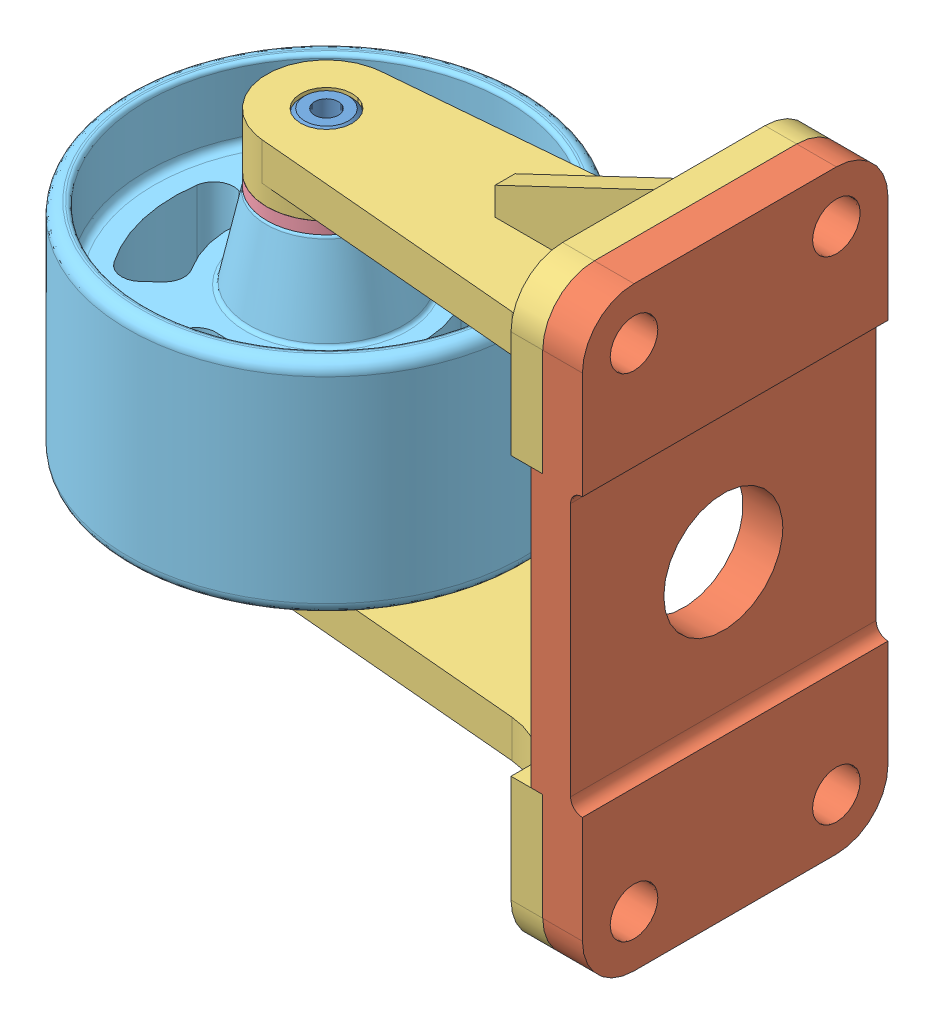
SolidWorks assembly 어셈블리1, configuration 기본. Lengths in mm.
Overall size (163.12 150 120.24).
7 component instances, 5 part files, 15 mates.
Components (placement in the parent):
- 250908_caster_axis-1: 250908_caster_axis [기본] at (-71.4492 13.4699 98) size (20 98 20)
- 250908_caster_base-1: 250908_caster_base [기본] at (31.5508 13.4699 98) x (0 1 0) z (0 0 1) size (150 13 77)
- 250908_caster_bracket-1: 250908_caster_bracket [기본] at (21.5508 -61.5301 98) x (0 0 1) z (0 -1 0) size (77 108 40)
- 250908_caster_bush-1: 250908_caster_bush [기본] at (-71.4492 -21.5301 98) x (0.41057 0 -0.911829) z (0.911829 0 0.41057) size (30 25 30)
- 250908_caster_wheel-1: 250908_caster_wheel [기본] at (-71.4492 14.4699 98) x (-0.228988 0 -0.973429) z (0.973429 0 -0.228988) size (100 62 100)
- 250908_caster_bracket-2: 250908_caster_bracket [기본] at (21.5508 88.4699 98) x (0 0 -1) z (0 1 0) size (77 108 40)
- 250908_caster_bush-3: 250908_caster_bush [기본] at (-71.4492 48.4699 98) x (-0.999987 0 0.00502) z (0.00502 0 0.999987) size (30 25 30)
Mates (geometry in assembly coordinates):
- 동심10: concentric: circle of 250908_caster_base-1; circle of 250908_caster_bracket-2
- 동심16: concentric: circle of 250908_caster_base-1; circle of 250908_caster_bracket-2
- 일치9: coincident: plane of 250908_caster_base-1 through (21.5508 13.4699 98) normal (-1 0 0); plane of 250908_caster_bracket-2 through (21.5508 75.4699 123.5) normal (1 0 0)
- 동심17: concentric: circle of 250908_caster_base-1; circle of 250908_caster_bracket-1
- 동심18: concentric: circle of 250908_caster_base-1; circle of 250908_caster_bracket-1
- 일치10: coincident: plane of 250908_caster_base-1 through (21.5508 13.4699 98) normal (-1 0 0); plane of 250908_caster_bracket-1 through (21.5508 -48.5301 72.5) normal (1 0 0)
- 동심19: concentric: circle of 250908_caster_axis-1; circle of 250908_caster_bracket-1
- 일치11: coincident: plane of 250908_caster_axis-1 through (-71.4492 62.4699 98) normal (0 1 0); plane of 250908_caster_bracket-2 through (-5.3969 62.4699 137.9087) normal (0 1 0)
- 일치18: coincident: plane of 250908_caster_wheel-1 through (-74.3115 45.4699 85.8321) normal (0 1 0); plane of 250908_caster_bush-3 through (-83.949 45.4699 98.0628) normal (0 -1 0)
- 동심23: concentric: circle of 250908_caster_axis-1; circle of 250908_caster_bush-3
- 일치20: coincident: plane of 250908_caster_bracket-2 through (-71.4492 48.4699 98) normal (0 -1 0); plane of 250908_caster_bush-3 through (-86.449 48.4699 98.0753) normal (0 1 0)
- 평행5: parallel: plane of 250908_caster_bracket-1 through (-71.4492 -21.5301 98) normal (0 1 0); plane of 250908_caster_bush-1 through (-65.2906 -21.5301 84.3226) normal (0 -1 0)
- 동심24: concentric: circle of 250908_caster_bracket-1; circle of 250908_caster_bush-1
- 일치22: coincident: plane of 250908_caster_bracket-1 through (-71.4492 -21.5301 98) normal (0 1 0); plane of 250908_caster_bush-1 through (-65.2906 -21.5301 84.3226) normal (0 -1 0)
- 동심25: concentric: circle of 250908_caster_bush-1; circle of 250908_caster_wheel-1
